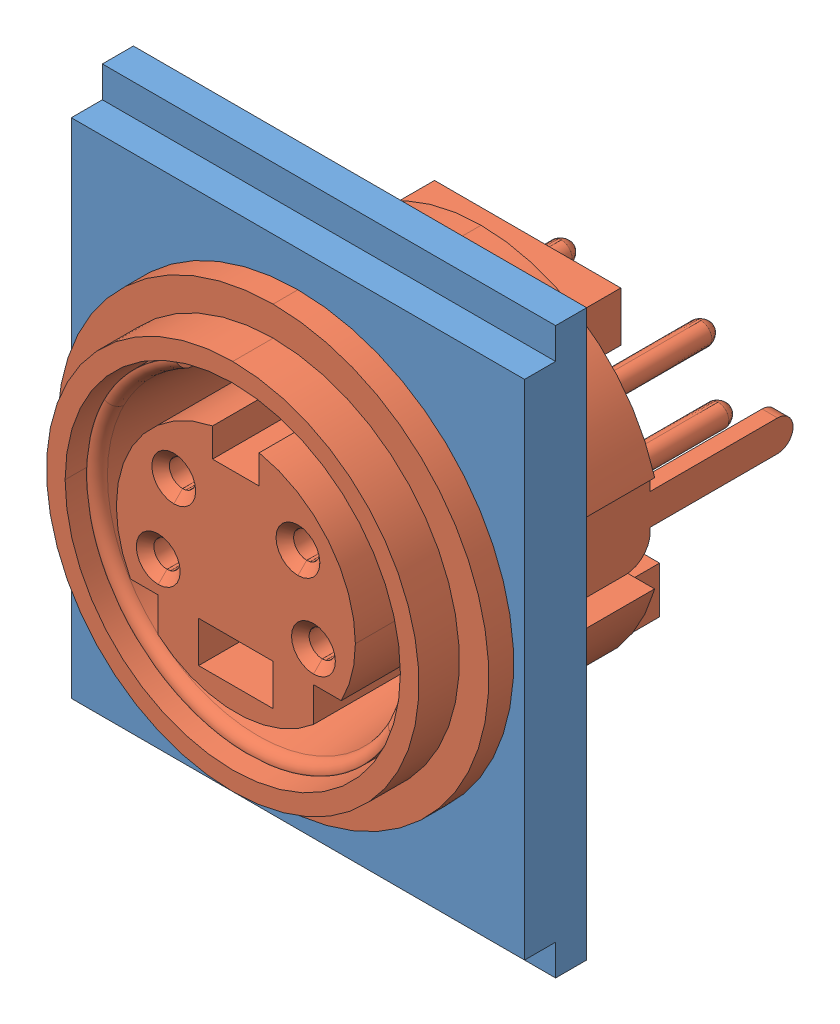
SolidWorks assembly Keystone-MiniDin, configuration Standard. Lengths in mm.
Overall size (14.6 18.2 13.2).
2 component instances, 2 part files, 6 mates.
Components (placement in the parent):
- Keystone-MiniDin-Loch-1: Keystone-MiniDin-Loch [Standard] at (-14.6 -17.2 0) x (-1 0 0) z (0 0 -1) size (14.6 18.2 2)
- anschluss_a-dio-top04-1: anschluss_a-dio-top04 [Standard] at (-7.3 -9.1 2.1) size (13.9 13.9 13.2)
Mates (geometry in assembly coordinates):
- Deckungsgleich1: coincident aligned: plane of Keystone-MiniDin-Loch-1 through (0 0 -2) normal (0 1 0); plane of assembly through (0 0 0) normal (0 1 0)
- Deckungsgleich2: coincident aligned: plane of Keystone-MiniDin-Loch-1 through (-14.6 -17.2 0) normal (0 0 1); plane of assembly through (0 0 0) normal (0 0 1)
- Deckungsgleich3: coincident aligned: plane of Keystone-MiniDin-Loch-1 through (0 -17.2 -1) normal (1 0 0); plane of assembly through (0 0 0) normal (1 0 0)
- Konzentrisch1: concentric anti-aligned: cylinder of Keystone-MiniDin-Loch-1 through (-7.3 -9.1 -10) axis (0 0 1) radius 5.8; cylinder of anschluss_a-dio-top04-1 through (-7.3 -9.1 -2.95) axis (0 0 -1) radius 5.8
- Deckungsgleich4: coincident anti-aligned: plane of Keystone-MiniDin-Loch-1 through (-14.6 -17.2 0) normal (0 0 1); plane of anschluss_a-dio-top04-1 through (-7.3 -15.475 0) normal (0 0 -1)
- Parallel1: parallel anti-aligned: plane of Keystone-MiniDin-Loch-1 through (-14.6 -17.2 -1) normal (0 -1 0); plane of anschluss_a-dio-top04-1 through (-7.3 -12.235 0.25) normal (0 1 0)
